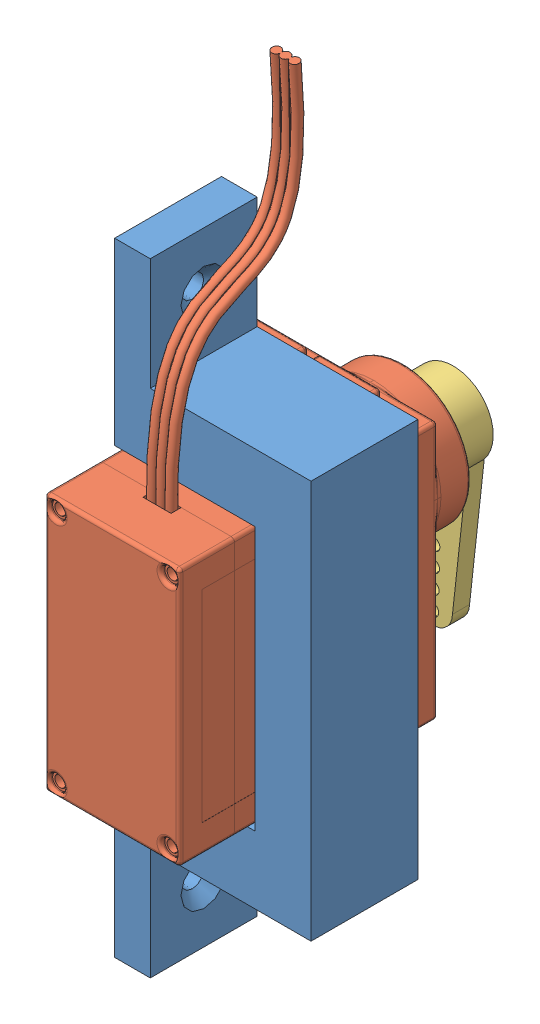
SolidWorks assembly cf_servo_assem, configuration Default. Lengths in mm.
Overall size (17.5 68.3 30.39).
3 component instances, 3 part files, 5 mates.
Components (placement in the parent):
- cf_servo_mount-1: cf_servo_mount [Default] at (18.7239 31.4581 41.9573) size (17.5 55.5 9.53)
- Servo HXT900 Micro-1: Servo HXT900 Micro [Valor predeterminado] at (12.4739 31.4581 57.9573) x (0 -1 0) z (1 0 0) size (57.05 29.01 12.2)
- Servo Arm HXT900 Micro-1: Servo Arm HXT900 Micro [Default] at (6.9751 37.07 24.7244) x (-0.999793 0.020337 0) z (0 0 -1) size (7.14 19.41 4.19)
Mates (geometry in assembly coordinates):
- Coincident1: coincident anti-aligned: plane of cf_servo_mount-1 through (18.7239 31.4581 41.9573) normal (0 0 -1); plane of Servo HXT900 Micro-1 through (12.4739 31.4581 41.9573) normal (0 0 1)
- Concentric1: concentric anti-aligned: cylinder of cf_servo_mount-1 through (12.4739 45.4581 41.9573) axis (0 0 -1) radius 1.016; cylinder of Servo HXT900 Micro-1 through (12.4739 45.4581 39.9573) axis (0 0 1) radius 1
- Concentric2: concentric anti-aligned: cylinder of cf_servo_mount-1 through (12.4739 17.4581 41.9573) axis (0 0 -1) radius 1.016; cylinder of Servo HXT900 Micro-1 through (12.4739 17.4581 39.9573) axis (0 0 1) radius 1
- Coincident2: coincident anti-aligned: plane of Servo HXT900 Micro-1 through (12.4739 36.9581 28.9573) normal (0 0 -1); plane of Servo Arm HXT900 Micro-1 through (12.4739 36.9581 28.9573) normal (0 0 1)
- Concentric3: concentric anti-aligned: cylinder of Servo HXT900 Micro-1 through (12.4739 36.9581 28.9573) axis (0 0 -1) radius 0.5; cylinder of Servo Arm HXT900 Micro-1 through (12.4739 36.9581 27.5663) axis (0 0 1) radius 2
